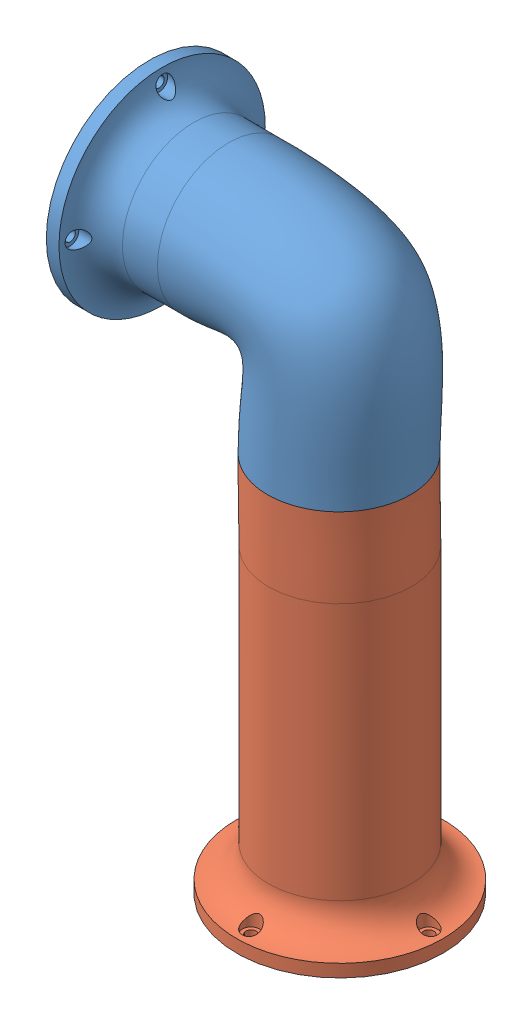
SolidWorks assembly Assem1, configuration Default. Lengths in mm.
Overall size (92.5 197.5 65).
2 component instances, 2 part files, 3 mates.
Components (placement in the parent):
- arm-1: arm [Default] at (16.5197 -98.5278 72.7442) size (85.15 97.5 65)
- arm_bottom-1: arm_bottom [Default] at (16.5197 -98.5278 72.7442) size (65 122.02 65)
Mates (geometry in assembly coordinates):
- Concentric1: concentric: cylinder of ? through (16.5197 -100.0278 72.7442) axis (0 1 0) radius 12; cylinder of ? through (16.5197 -98.5278 72.7442) axis (0 1 0) radius 22.5
- Parallel1: parallel: plane of ? through (2.6197 1.4722 86.6442) normal (-1 0 0); plane of ? through (2.5197 -98.5278 86.7442) normal (1 0 0)
- Coincident2: coincident: plane of ? through (16.5197 21.4722 72.7442) normal (0 -1 0); plane of ? through (16.5197 21.4722 72.7442) normal (0 1 0)
